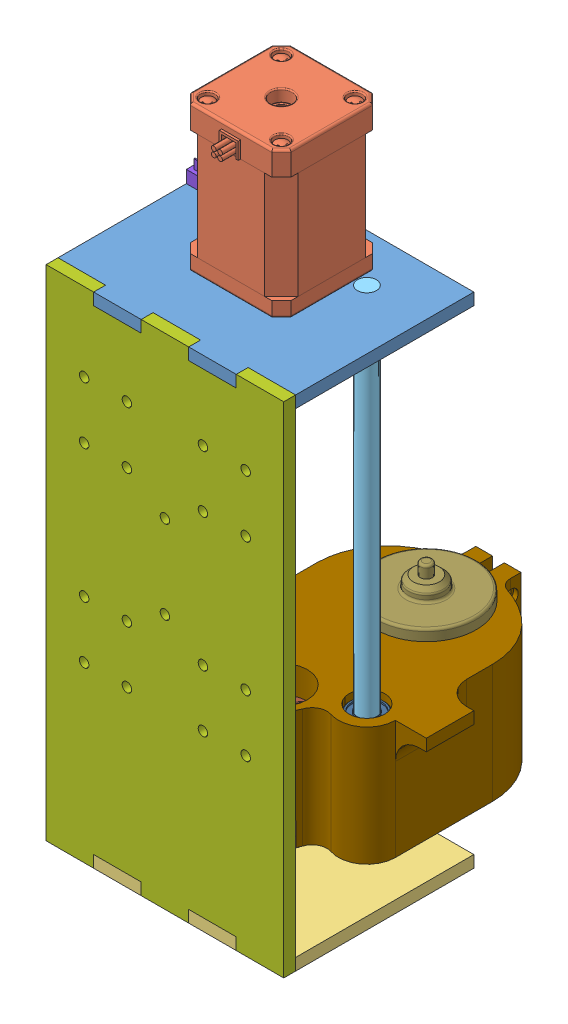
SolidWorks assembly Z Axis Assem, configuration Default. Lengths in mm.
Overall size (100 296.1 140.35).
15 component instances, 12 part files, 25 mates.
Components (placement in the parent):
- Z-Axis_Stepper Side-1: Z-Axis_Stepper Side [Default] at (272.4024 497.0443 418.9709) x (-1 0 0) z (0 0 -1) size (100 5 80)
- Nema 17 Steper Motor-1: Nema 17 Steper Motor [Default] at (291.0231 579.206 382.1217) x (-1 0 0) z (0 0 1) size (42.3 87.55 48.3)
- Z-Axis Side-1: Z-Axis Side [Default] at (272.4024 292.0443 418.9709) x (-1 0 0) z (0 0 -1) size (100 5 80)
- 608 - 2RS-1: 608 - 2RS [Default] at (272.4024 293.5443 418.9709) x (-0.599684 0 -0.800237) z (0 1 0) size (22 22 7)
- Z-Axis_Soft rod-1: Z-Axis_Soft rod [Default] at (247.4024 502.0443 407.9709) x (1 0 0) z (0 -1 0) size (8 8 220)
- Z-Axis_Soft rod-2: Z-Axis_Soft rod [Default] at (297.4024 502.0443 407.9709) x (1 0 0) z (0 -1 0) size (8 8 220)
- Z-Axis_Soft Screw M8×13 cm-1: Z-Axis_Soft Screw M8×13 cm [Default] at (272.4024 475.9968 418.9709) x (1 0 0) z (0 -1 0) size (8 8 175)
- Z-Axis_Base(NEW)-1: Z-Axis_Base(NEW) [Default] at (272.4024 417.0443 462.9709) size (100 210 5)
- Limit Switch-2: Limit Switch [Default] at (225.6024 504.7443 394.3709) x (0 0 -1) z (-1 0 0) size (19.8 20 6.4)
- New Z Assem-1: New Z Assem [Default] at (281.3611 279.6804 466.9332) x (-1 0 0) z (0 0 -1) size (100 96.7 105.35)
  - New Z-1: New Z [Default] at (8.9587 19.7661 58.9622) size (100 50 105.35)
  - LM8LUU Long Type Linear Bearing-1: LM8LUU Long Type Linear Bearing [Default] at (-16.0413 67.2661 58.9622) x (0 -1 0) z (0 0 1) size (45 15 15)
  - LM8LUU Long Type Linear Bearing-2: LM8LUU Long Type Linear Bearing [Default] at (33.9587 67.2661 58.9622) x (0 -1 0) z (0 0 1) size (45 15 15)
  - LeadScrew Nut 8mm x 2mmPitch-1: LeadScrew Nut 8mm x 2mmPitch [Default] at (8.9587 58.2661 47.9622) x (1 0 0) z (0 1 0) size (22 22 16.05)
  - High Speed 775 Motor Low Noise DC 12V-24V Large Torque Motor Ball Bearing Tools-1: High Speed 775 Motor Low Noise DC 12V-24V Large Torque Motor Ball Bearing Tools [Default] at (8.9587 74.4661 108.9622) x (0 -1 0) z (0 0 1) size (96.7 43.88 45)
Mates (geometry in assembly coordinates):
- Coincident52: coincident: plane of assembly; plane of assembly; plane of Z-Axis_Stepper Side-1 through (272.4024 502.0443 418.9709) normal (0 1 0); plane of Nema 17 Steper Motor-1 through (272.4024 502.0443 418.9709) normal (0 -1 0)
- Parallel13: parallel: cylinder of assembly; cylinder of assembly; cylinder of Nema 17 Steper Motor-1 through (287.9024 508.5443 403.4709) axis (0 -1 0) radius 1.5; cylinder of Z-Axis_Stepper Side-1 through (287.9024 502.0443 403.4709) axis (0 -1 0) radius 1.5
- Coincident56: coincident: cylinder of assembly; circle of assembly; cylinder of Z-Axis_Stepper Side-1 through (256.9024 502.0443 403.4709) axis (0 -1 0) radius 1.5; circle of Nema 17 Steper Motor-1
- Concentric26: concentric: cylinder of assembly; cylinder of assembly; cylinder of Z-Axis_Stepper Side-1 through (287.9024 502.0443 403.4709) axis (0 -1 0) radius 1.5; cylinder of Nema 17 Steper Motor-1 through (287.9024 508.5443 403.4709) axis (0 -1 0) radius 1.5
- Coincident60: coincident: plane of assembly; plane of assembly; plane of Z-Axis_Stepper Side-1 through (272.4024 502.0443 418.9709) normal (0 1 0); plane of Z-Axis_Soft rod-1 through (247.4024 502.0443 407.9709) normal (0 1 0)
- Coincident61: coincident: plane of assembly; plane of assembly; plane of Z-Axis_Stepper Side-1 through (272.4024 502.0443 418.9709) normal (0 1 0); plane of Z-Axis_Soft rod-2 through (297.4024 502.0443 407.9709) normal (0 1 0)
- Concentric31: concentric: cylinder of assembly; cylinder of assembly; cylinder of Z-Axis_Stepper Side-1 through (297.4024 502.0443 407.9709) axis (0 -1 0) radius 4; cylinder of Z-Axis_Soft rod-2 through (297.4024 282.0443 407.9709) axis (0 1 0) radius 4
- Coincident77: coincident: plane of assembly; plane of assembly; plane of Z-Axis_Stepper Side-1 through (282.4024 502.0443 462.9709) normal (0 0 1); plane of Z-Axis_Base(NEW)-1 through (272.4024 417.0443 462.9709) normal (0 0 -1)
- Coincident81: coincident: plane of assembly; plane of assembly; plane of Z-Axis_Stepper Side-1 through (262.4024 502.0443 467.9709) normal (0 0 1); plane of Z-Axis_Base(NEW)-1 through (272.4024 417.0443 467.9709) normal (0 0 1)
- Coincident82: coincident: plane of assembly; plane of assembly; plane of Z-Axis_Stepper Side-1 through (272.4024 502.0443 418.9709) normal (0 1 0); plane of Z-Axis_Base(NEW)-1 through (222.4024 502.0443 467.9709) normal (0 1 0)
- Coincident83: coincident: plane of assembly; plane of assembly; plane of Z-Axis_Stepper Side-1 through (322.4024 502.0443 387.9709) normal (1 0 0); plane of Z-Axis_Base(NEW)-1 through (322.4024 502.0443 467.9709) normal (1 0 0)
- Coincident62: coincident: plane of assembly; plane of assembly; plane of Nema 17 Steper Motor-1 through (272.4024 475.9968 418.9709) normal (0 -1 0); plane of Z-Axis_Soft Screw M8×13 cm-1 through (272.4024 475.9968 418.9709) normal (0 1 0)
- Concentric32: concentric: cylinder of assembly; cylinder of assembly; cylinder of Nema 17 Steper Motor-1 through (272.4024 475.9968 418.9709) axis (0 -1 0) radius 2.5; cylinder of Z-Axis_Soft Screw M8×13 cm-1 through (272.4024 300.9968 418.9709) axis (0 1 0) radius 4
- Concentric28: concentric: cylinder of assembly; cylinder of assembly; cylinder of Z-Axis Side-1 through (272.4024 292.0433 418.9709) axis (0 1 0) radius 11; cylinder of 608 - 2RS-1 through (272.4024 297.0443 418.9709) axis (0 -1 0) radius 11
- Concentric30: concentric: cylinder of assembly; cylinder of assembly; cylinder of Z-Axis Side-1 through (247.4024 297.0443 407.9709) axis (0 -1 0) radius 4; cylinder of Z-Axis_Soft rod-1 through (247.4024 282.0443 407.9709) axis (0 1 0) radius 4
- Coincident84: coincident: plane of assembly; plane of assembly; plane of Z-Axis Side-1 through (322.4024 297.0443 387.9709) normal (1 0 0); plane of Z-Axis_Base(NEW)-1 through (322.4024 502.0443 467.9709) normal (1 0 0)
- Coincident85: coincident: plane of assembly; plane of assembly; plane of Z-Axis Side-1 through (272.4024 292.0443 418.9709) normal (0 -1 0); plane of Z-Axis_Base(NEW)-1 through (222.4024 292.0443 467.9709) normal (0 -1 0)
- Coincident86: coincident: plane of assembly; plane of assembly; plane of Z-Axis Side-1 through (302.4024 297.0443 467.9709) normal (0 0 1); plane of Z-Axis_Base(NEW)-1 through (272.4024 417.0443 467.9709) normal (0 0 1)
- Coincident95: coincident: plane of assembly; plane of assembly; plane of Z-Axis Side-1 through (272.4024 297.0443 418.9709) normal (0 1 0); plane of 608 - 2RS-1 through (272.4024 297.0443 418.9709) normal (0 1 0)
- Parallel19: parallel: plane of assembly; plane of assembly; plane of Z-Axis_Base(NEW)-1 through (272.4024 417.0443 462.9709) normal (0 0 -1); plane of Limit Switch-2 through (222.4024 507.2443 408.9709) normal (0 0 1)
- Coincident100: coincident: plane of Z-Axis_Stepper Side-1 through (272.4024 497.0443 418.9709) normal (0 -1 0); plane of Limit Switch-2 through (222.4024 497.0443 408.9709) normal (0 -1 0)
- Coincident101: coincident: plane of Z-Axis_Stepper Side-1 through (222.4024 502.0443 387.9709) normal (-1 0 0); plane of Limit Switch-2 through (222.4024 507.2443 389.1709) normal (-1 0 0)
- Coincident102: coincident: plane of Z-Axis_Stepper Side-1 through (229.4024 497.0443 408.9709) normal (0 0 -1); plane of Limit Switch-2 through (222.4024 507.2443 408.9709) normal (0 0 1)
- Concentric33: concentric: cylinder of assembly; cylinder of assembly; cylinder of Z-Axis_Soft rod-1 through (247.4024 282.0443 407.9709) axis (0 1 0) radius 4; cylinder of New Z Assem-1/LM8LUU Long Type Linear Bearing-2 through (247.4024 346.9465 407.9709) axis (0 1 0) radius 4.175
- Concentric34: concentric: cylinder of assembly; cylinder of assembly; cylinder of Z-Axis_Soft rod-2 through (297.4024 282.0443 407.9709) axis (0 1 0) radius 4; cylinder of New Z Assem-1/LM8LUU Long Type Linear Bearing-1 through (297.4024 346.9465 407.9709) axis (0 1 0) radius 4.175
